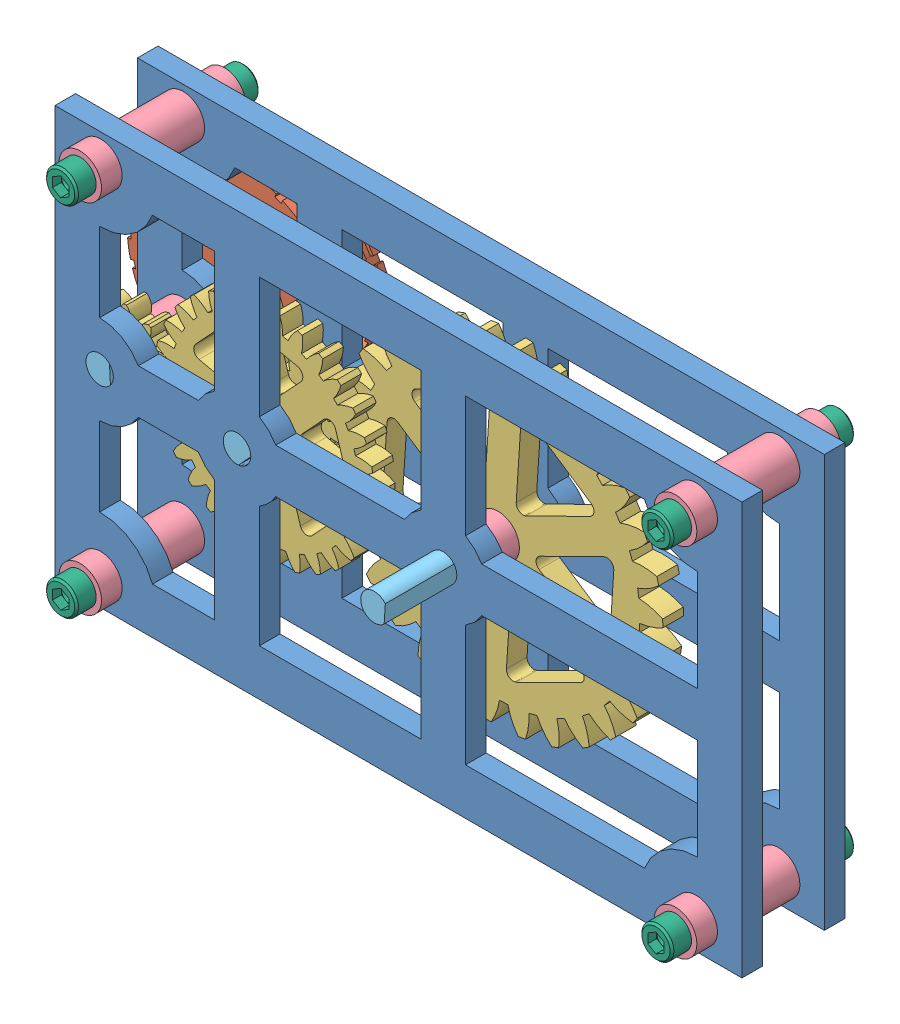
SolidWorks assembly gearbox, configuration Default. Lengths in mm.
Overall size (110.32 60.05 37).
40 component instances, 6 part files, 55 mates.
Components (placement in the parent):
- plate-1: plate [Default] at (70.9322 77.6534 104.1994) size (100 60 3)
- plate-2: plate [Default] at (70.9322 77.6534 92.1994) size (100 60 3)
- knob-1: knob [Default] at (27.4322 77.6534 87.1994) x (0.0533 -0.998579 0) z (0 0 1) size (31.98 31.99 7)
- input#2(30T-1.0Mod 15mm shaft)-1: input#2(30T-1.0Mod 15mm shaft) [Default] at (45.857 87.2731 87.3213) x (-0.678523 -0.734579 0) z (0 0 1) size (32 31.89 15)
  - root_gear.-1: root_gear. [30T1.0Mod] at (5.9976 7.6843 12.878) size (32 31.89 3)
  - root_gear.-2: root_gear. [10T 1.5Mod] at (5.9976 7.6843 8.878) size (18 17.3 3)
  - spacer-1: spacer [4.2 1mm] at (5.9976 7.6843 15.878) size (6.2 6.2 1)
  - spacer-2: spacer [4.2 1mm] at (5.9976 7.6843 11.878) x (0.997387 0.07225 0) z (0 0 1) size (6.2 6.2 1)
  - spacer-5: spacer [4.2 1mm] at (5.9976 7.6843 7.878) x (0.9453 0.326202 0) z (0 0 1) size (6.2 6.2 1)
  - axle-2: axle [axle15] at (5.9976 7.6843 4.878) size (4 3.5 15)
- input#3(30T1.5-25mm)-1: input#3(30T1.5-25mm) [Default] at (44.0793 92.2173 63.6583) x (-0.065413 -0.997858 0) z (0 0 1) size (48 47.84 25)
  - root_gear.-1: root_gear. [30T 1.5Mod] at (12.351 34.2341 32.5411) size (48 47.84 3)
  - axle-1: axle [axle25] at (12.351 34.2341 28.5411) size (4 3.5 25)
  - spacer-1: spacer [4.2] at (12.351 34.2341 35.5411) size (6.2 6.2 5)
  - spacer-2: spacer [4.2 1mm] at (12.351 34.2341 31.5411) size (6.2 6.2 1)
- inputShaft-1: inputShaft [Default] at (21.1329 92.7856 104.8181) x (0.0533 -0.998579 0) z (0 0 1) size (12 11.53 25)
  - axle-1: axle [axle25] at (15.4465 5.4837 -22.6187) size (4 3.5 25)
  - root_gear.-1: root_gear. [10T1.0Mod] at (15.4314 5.4837 -4.6187) size (12 11.53 3)
  - spacer-3: spacer [4.2 1mm] at (15.4465 5.4837 -1.6187) size (6.2 6.2 1)
  - spacer-4: spacer [4.2-5] at (15.4465 5.4837 -9.6187) size (6.2 6.2 5)
- spacer-1: spacer [2.85] at (114.2655 103.6534 95.1994) size (6.2 6.2 9)
- spacer-2: spacer [2.85] at (27.5988 103.6534 95.1994) size (6.2 6.2 9)
- spacer-3: spacer [2.85] at (27.5988 51.6534 104.1994) x (0.923728 0.383049 0) z (0 0 -1) size (6.2 6.2 9)
- spacer-4: spacer [2.85] at (114.2655 51.6534 104.1994) x (0.923728 0.383049 0) z (0 0 -1) size (6.2 6.2 9)
- spacer-6: spacer [3] at (27.5988 103.6534 107.1994) size (6.2 6.2 3)
- spacer-7: spacer [3] at (114.2655 103.6534 107.1994) size (6.2 6.2 3)
- spacer-8: spacer [3] at (114.2655 51.6534 107.1994) size (6.2 6.2 3)
- spacer-9: spacer [3] at (27.5988 51.6534 107.1994) size (6.2 6.2 3)
- spacer-10: spacer [3] at (114.2655 103.6534 89.1994) size (6.2 6.2 3)
- spacer-11: spacer [3] at (27.5988 103.6534 89.1994) size (6.2 6.2 3)
- spacer-12: spacer [3] at (27.5988 51.6534 89.1994) size (6.2 6.2 3)
- spacer-13: spacer [3] at (114.2655 51.6534 89.1994) size (6.2 6.2 3)
- socket head cap screw_ai-9: socket head cap screw_ai [HX-SHCS 0.112-40x0.375x0.375-N] at (27.5988 103.6534 86.3546) x (0 0 1) z (-1 0 0) size (12.37 4.65 4.65)
- socket head cap screw_ai-10: socket head cap screw_ai [HX-SHCS 0.112-40x0.375x0.375-N] at (27.5988 103.6534 113.0442) x (0 0 -1) z (1 0 0) size (12.37 4.65 4.65)
- socket head cap screw_ai-11: socket head cap screw_ai [HX-SHCS 0.112-40x0.375x0.375-N] at (27.5988 51.6534 113.0442) x (0 0 -1) z (1 0 0) size (12.37 4.65 4.65)
- socket head cap screw_ai-12: socket head cap screw_ai [HX-SHCS 0.112-40x0.375x0.375-N] at (27.5988 51.6534 86.3546) x (0 0 1) z (-1 0 0) size (12.37 4.65 4.65)
- socket head cap screw_ai-13: socket head cap screw_ai [HX-SHCS 0.112-40x0.375x0.375-N] at (114.2655 51.6534 86.3546) x (0 0 1) z (-1 0 0) size (12.37 4.65 4.65)
- socket head cap screw_ai-14: socket head cap screw_ai [HX-SHCS 0.112-40x0.375x0.375-N] at (114.2655 51.6534 113.0442) x (0 0 -1) z (1 0 0) size (12.37 4.65 4.65)
- socket head cap screw_ai-15: socket head cap screw_ai [HX-SHCS 0.112-40x0.375x0.375-N] at (114.2655 103.6534 113.0442) x (0 0 -1) z (1 0 0) size (12.37 4.65 4.65)
- socket head cap screw_ai-16: socket head cap screw_ai [HX-SHCS 0.112-40x0.375x0.375-N] at (114.2655 103.6534 86.3546) x (0 0 1) z (-1 0 0) size (12.37 4.65 4.65)
Mates (geometry in assembly coordinates):
- Concentric4: concentric aligned: cylinder of plate-1 through (77.4322 77.6534 114.1994) axis (0 0 -1) radius 2; cylinder of input#3(30T1.5-25mm)-1/axle-1 through (77.4322 77.6534 117.1994) axis (0 0 -1) radius 2
- Coincident3: coincident anti-aligned: plane of plate-1 through (70.9322 77.6534 104.1994) normal (0 0 -1); plane of input#3(30T1.5-25mm)-1/spacer-1 through (77.4322 77.6534 104.1994) normal (0 0 1)
- Concentric5: concentric aligned: cylinder of plate-1 through (47.4322 77.6534 114.1994) axis (0 0 -1) radius 2; cylinder of input#2(30T-1.0Mod 15mm shaft)-1/axle-1 through (47.4322 77.6534 109.1994) axis (0 0 -1) radius 2
- Coincident4: coincident anti-aligned: plane of plate-1 through (70.9322 77.6534 104.1994) normal (0 0 -1); plane of input#2(30T-1.0Mod 15mm shaft)-1/spacer-1 through (47.4322 77.6534 104.1994) normal (0 0 1)
- Concentric7: concentric aligned: cylinder of plate-1 through (27.4322 77.6534 114.1994) axis (0 0 -1) radius 2; cylinder of inputShaft-1/axle-1 through (27.4322 77.6534 107.1994) axis (0 0 -1) radius 2
- Coincident9: coincident anti-aligned: plane of plate-1 through (70.9322 77.6534 104.1994) normal (0 0 -1); plane of inputShaft-1/spacer-3 through (27.4322 77.6534 104.1994) normal (0 0 1)
- GearMate4: gear = 1 : 3 mm: circle of input#2(30T-1.0Mod 15mm shaft)-1/root_gear.-1; circle of inputShaft-1/root_gear.-1
- GearMate7: gear = 1 : 3 mm: circle of input#3(30T1.5-25mm)-1/root_gear.-1; circle of input#2(30T-1.0Mod 15mm shaft)-1/root_gear.-2
- Concentric8: concentric aligned: cylinder of plate-1 through (47.4322 77.6534 114.1994) axis (0 0 -1) radius 2; cylinder of input#2(30T-1.0Mod 15mm shaft)-1/axle-2 through (47.4322 77.6534 107.1994) axis (0 0 -1) radius 2
- Coincident10: coincident anti-aligned: plane of plate-1 through (70.9322 77.6534 104.1994) normal (0 0 -1); circle of spacer-2
- Concentric10: concentric aligned: cylinder of plate-1 through (27.5988 103.6534 114.1994) axis (0 0 -1) radius 1.5; cylinder of spacer-2 through (27.5988 103.6534 104.1994) axis (0 0 -1) radius 1.425
- Concentric11: concentric aligned: cylinder of plate-1 through (114.2655 103.6534 114.1994) axis (0 0 -1) radius 1.5; cylinder of spacer-1 through (114.2655 103.6534 104.1994) axis (0 0 -1) radius 1.425
- Concentric12: concentric anti-aligned: cylinder of plate-1 through (114.2655 51.6534 114.1994) axis (0 0 -1) radius 1.5; cylinder of spacer-4 through (114.2655 51.6534 95.1994) axis (0 0 1) radius 1.425
- Concentric13: concentric anti-aligned: cylinder of plate-1 through (27.5988 51.6534 114.1994) axis (0 0 -1) radius 1.5; cylinder of spacer-3 through (27.5988 51.6534 95.1994) axis (0 0 1) radius 1.425
- Coincident11: coincident anti-aligned: plane of plate-1 through (70.9322 77.6534 104.1994) normal (0 0 -1); plane of spacer-1 through (114.2655 103.6534 104.1994) normal (0 0 1)
- Coincident12: coincident anti-aligned: plane of plate-1 through (70.9322 77.6534 104.1994) normal (0 0 -1); plane of spacer-4 through (114.2655 51.6534 104.1994) normal (0 0 1)
- Coincident13: coincident anti-aligned: plane of plate-1 through (70.9322 77.6534 104.1994) normal (0 0 -1); plane of spacer-3 through (27.5988 51.6534 104.1994) normal (0 0 1)
- Concentric14: concentric aligned: cylinder of plate-2 through (114.2655 103.6534 102.1994) axis (0 0 -1) radius 1.5; cylinder of spacer-10 through (114.2655 103.6534 92.1994) axis (0 0 -1) radius 1.5
- Coincident14: coincident anti-aligned: plane of plate-2 through (70.9322 77.6534 92.1994) normal (0 0 -1); plane of spacer-10 through (114.2655 103.6534 92.1994) normal (0 0 1)
- Coincident15: coincident anti-aligned: plane of plate-2 through (70.9322 77.6534 92.1994) normal (0 0 -1); plane of spacer-11 through (27.5988 103.6534 92.1994) normal (0 0 1)
- Concentric15: concentric aligned: cylinder of plate-2 through (27.5988 103.6534 102.1994) axis (0 0 -1) radius 1.5; cylinder of spacer-11 through (27.5988 103.6534 92.1994) axis (0 0 -1) radius 1.5
- Concentric16: concentric aligned: cylinder of plate-2 through (27.5988 51.6534 102.1994) axis (0 0 -1) radius 1.5; cylinder of spacer-12 through (27.5988 51.6534 92.1994) axis (0 0 -1) radius 1.5
- Coincident16: coincident anti-aligned: plane of plate-2 through (70.9322 77.6534 92.1994) normal (0 0 -1); plane of spacer-12 through (27.5988 51.6534 92.1994) normal (0 0 1)
- Concentric17: concentric aligned: cylinder of plate-2 through (114.2655 51.6534 102.1994) axis (0 0 -1) radius 1.5; cylinder of spacer-13 through (114.2655 51.6534 92.1994) axis (0 0 -1) radius 1.5
- Coincident17: coincident anti-aligned: plane of plate-2 through (70.9322 77.6534 92.1994) normal (0 0 -1); plane of spacer-13 through (114.2655 51.6534 92.1994) normal (0 0 1)
- Concentric18: concentric aligned: cylinder of plate-1 through (114.2655 103.6534 114.1994) axis (0 0 -1) radius 1.5; cylinder of spacer-7 through (114.2655 103.6534 110.1994) axis (0 0 -1) radius 1.5
- Coincident18: coincident anti-aligned: plane of plate-1 through (70.9322 77.6534 107.1994) normal (0 0 1); plane of spacer-7 through (114.2655 103.6534 107.1994) normal (0 0 -1)
- Concentric19: concentric aligned: cylinder of plate-1 through (114.2655 51.6534 114.1994) axis (0 0 -1) radius 1.5; cylinder of spacer-8 through (114.2655 51.6534 110.1994) axis (0 0 -1) radius 1.5
- Coincident19: coincident anti-aligned: plane of plate-1 through (70.9322 77.6534 107.1994) normal (0 0 1); plane of spacer-8 through (114.2655 51.6534 107.1994) normal (0 0 -1)
- Coincident20: coincident anti-aligned: plane of plate-1 through (70.9322 77.6534 107.1994) normal (0 0 1); plane of spacer-6 through (27.5988 103.6534 107.1994) normal (0 0 -1)
- Concentric20: concentric aligned: cylinder of plate-1 through (27.5988 103.6534 114.1994) axis (0 0 -1) radius 1.5; cylinder of spacer-6 through (27.5988 103.6534 110.1994) axis (0 0 -1) radius 1.5
- Coincident21: coincident anti-aligned: plane of plate-1 through (70.9322 77.6534 107.1994) normal (0 0 1); plane of spacer-9 through (27.5988 51.6534 107.1994) normal (0 0 -1)
- Concentric22: concentric aligned: cylinder of plate-1 through (27.5988 51.6534 114.1994) axis (0 0 -1) radius 1.5; cylinder of spacer-9 through (27.5988 51.6534 110.1994) axis (0 0 -1) radius 1.5
- Concentric23: concentric aligned: cylinder of plate-2 through (27.5988 103.6534 102.1994) axis (0 0 -1) radius 1.5; cylinder of spacer-2 through (27.5988 103.6534 104.1994) axis (0 0 -1) radius 1.425
- Concentric24: concentric aligned: cylinder of spacer-1 through (114.2655 103.6534 104.1994) axis (0 0 -1) radius 1.425; cylinder of spacer-10 through (114.2655 103.6534 92.1994) axis (0 0 -1) radius 1.5
- Coincident22: coincident aligned: plane of plate-2 through (70.9322 77.6534 92.1994) normal (0 0 -1); plane of input#3(30T1.5-25mm)-1/axle-1 through (77.4322 77.6534 92.1994) normal (0 0 -1)
- Concentric25: concentric anti-aligned: cylinder of knob-1 through (27.4322 77.6534 87.1994) axis (0 0 1) radius 2; cylinder of inputShaft-1/axle-1 through (27.4322 77.6534 107.1994) axis (0 0 -1) radius 2
- Parallel1: parallel aligned: plane of knob-1 through (38.9158 78.2664 84.2994) normal (0.998579 0.0533 0); plane of inputShaft-1/axle-1 through (28.8595 79.0544 107.1994) normal (0.998579 0.0533 0)
- Coincident24: coincident aligned: plane of knob-1 through (27.4322 77.6534 82.1994) normal (0 0 -1); plane of inputShaft-1/axle-1 through (27.4322 77.6534 82.1994) normal (0 0 -1)
- Concentric26: concentric aligned: cylinder of spacer-11 through (27.5988 103.6534 92.1994) axis (0 0 -1) radius 1.5; cylinder of socket head cap screw_ai-9 through (27.5988 103.6534 54.6046) axis (0 0 -1) radius 2.3241
- Coincident25: coincident anti-aligned: plane of spacer-11 through (27.5988 103.6534 89.1994) normal (0 0 -1); plane of socket head cap screw_ai-9 through (27.5988 105.9775 89.1994) normal (0 0 1)
- Concentric27: concentric anti-aligned: cylinder of spacer-6 through (27.5988 103.6534 110.1994) axis (0 0 -1) radius 1.5; cylinder of socket head cap screw_ai-10 through (27.5988 103.6534 144.7942) axis (0 0 1) radius 2.3241
- Coincident26: coincident anti-aligned: plane of spacer-6 through (27.5988 103.6534 110.1994) normal (0 0 1); plane of socket head cap screw_ai-10 through (27.5988 105.9775 110.1994) normal (0 0 -1)
- Concentric28: concentric anti-aligned: cylinder of spacer-9 through (27.5988 51.6534 110.1994) axis (0 0 -1) radius 3.1; cylinder of socket head cap screw_ai-11 through (27.5988 51.6534 144.7942) axis (0 0 1) radius 2.3241
- Coincident27: coincident anti-aligned: plane of spacer-9 through (27.5988 51.6534 110.1994) normal (0 0 1); plane of socket head cap screw_ai-11 through (27.5988 53.9775 110.1994) normal (0 0 -1)
- Concentric29: concentric aligned: cylinder of spacer-12 through (27.5988 51.6534 92.1994) axis (0 0 -1) radius 3.1; cylinder of socket head cap screw_ai-12 through (27.5988 51.6534 54.6046) axis (0 0 -1) radius 2.3241
- Coincident28: coincident anti-aligned: plane of spacer-12 through (27.5988 51.6534 89.1994) normal (0 0 -1); plane of socket head cap screw_ai-12 through (27.5988 53.9775 89.1994) normal (0 0 1)
- Concentric30: concentric aligned: cylinder of spacer-13 through (114.2655 51.6534 92.1994) axis (0 0 -1) radius 1.5; cylinder of socket head cap screw_ai-13 through (114.2655 51.6534 54.6046) axis (0 0 -1) radius 2.3241
- Coincident29: coincident anti-aligned: plane of spacer-13 through (114.2655 51.6534 89.1994) normal (0 0 -1); plane of socket head cap screw_ai-13 through (114.2655 53.9775 89.1994) normal (0 0 1)
- Concentric31: concentric anti-aligned: cylinder of spacer-8 through (114.2655 51.6534 110.1994) axis (0 0 -1) radius 3.1; cylinder of socket head cap screw_ai-14 through (114.2655 51.6534 144.7942) axis (0 0 1) radius 2.3241
- Coincident30: coincident anti-aligned: plane of spacer-8 through (114.2655 51.6534 110.1994) normal (0 0 1); plane of socket head cap screw_ai-14 through (114.2655 53.9775 110.1994) normal (0 0 -1)
- Concentric32: concentric anti-aligned: cylinder of spacer-7 through (114.2655 103.6534 110.1994) axis (0 0 -1) radius 1.5; cylinder of socket head cap screw_ai-15 through (114.2655 103.6534 144.7942) axis (0 0 1) radius 2.3241
- Coincident31: coincident anti-aligned: plane of spacer-7 through (114.2655 103.6534 110.1994) normal (0 0 1); plane of socket head cap screw_ai-15 through (114.2655 105.9775 110.1994) normal (0 0 -1)
- Concentric33: concentric aligned: cylinder of spacer-10 through (114.2655 103.6534 92.1994) axis (0 0 -1) radius 1.5; cylinder of socket head cap screw_ai-16 through (114.2655 103.6534 54.6046) axis (0 0 -1) radius 2.3241
- Coincident32: coincident anti-aligned: plane of spacer-10 through (114.2655 103.6534 89.1994) normal (0 0 -1); plane of socket head cap screw_ai-16 through (114.2655 105.9775 89.1994) normal (0 0 1)
